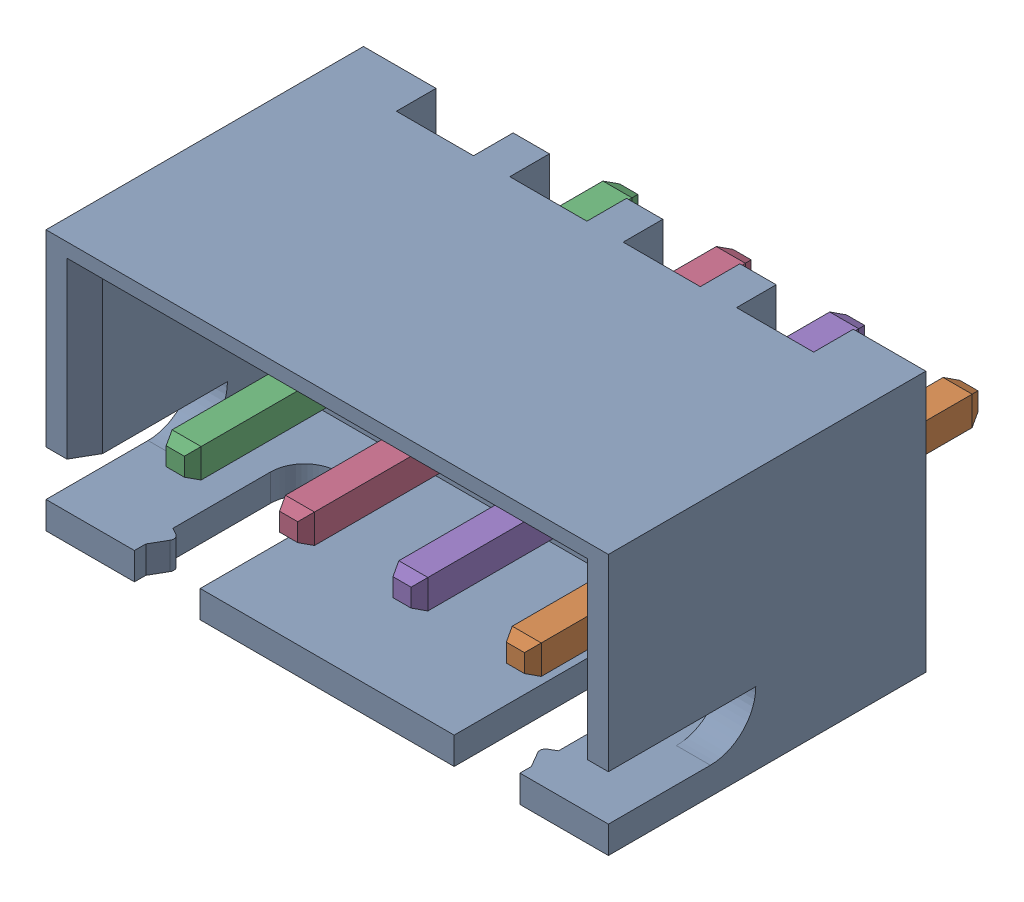
SolidWorks assembly JST-XH-4POS-VERT, configuration Default. Lengths in mm.
Overall size (12.4 5.75 10.4).
5 component instances, 2 part files, 0 mates.
Components (placement in the parent):
- Plastic-1: Plastic [Default] at (0 -2.875 0) size (12.4 5.75 7)
- Pin-1: Pin [Default] at (3.75 -0.525 1.6) size (0.64 0.64 10)
- Pin-2: Pin [Default] at (-3.75 -0.525 1.6) size (0.64 0.64 10)
- Pin-3: Pin [Default] at (-1.25 -0.525 1.6) size (0.64 0.64 10)
- Pin-4: Pin [Default] at (1.25 -0.525 1.6) size (0.64 0.64 10)
